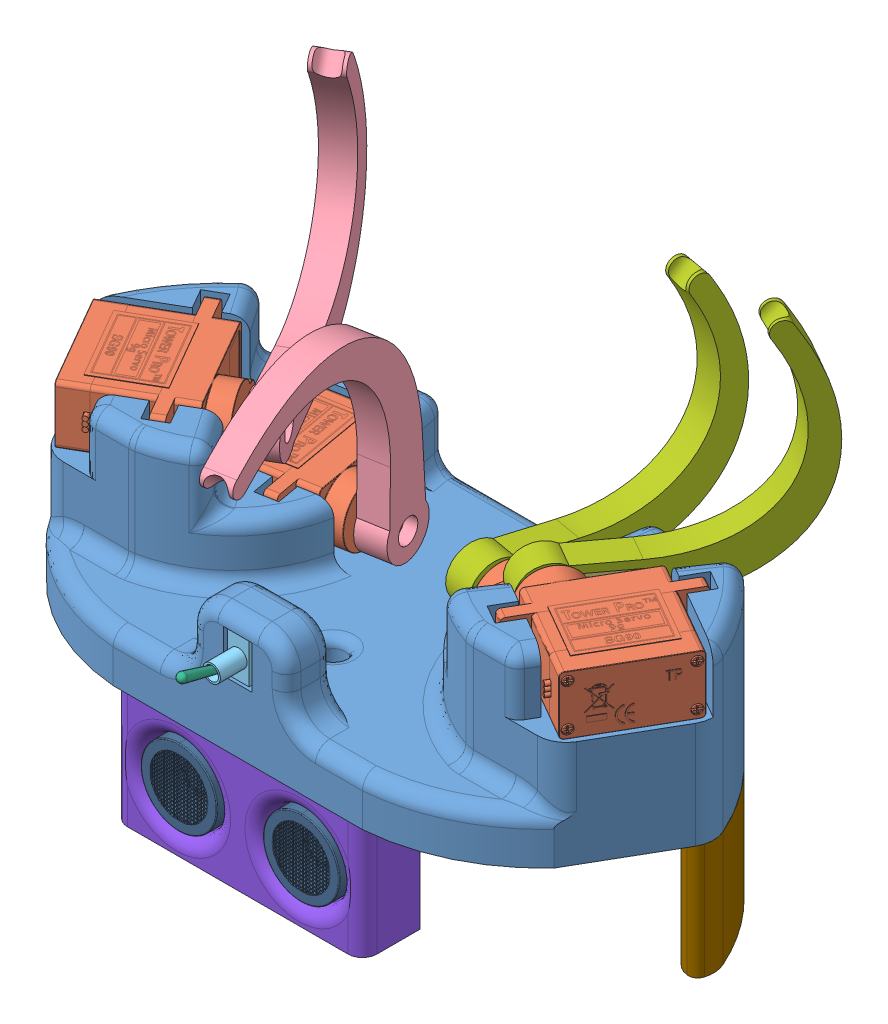
SolidWorks assembly ASSEMBLY, configuration Default. Lengths in mm.
Overall size (132.6 96.26 103.99).
20 component instances, 11 part files, 48 mates.
Components (placement in the parent):
- Body V1-1: Body V1 [Default] at (-17.087 -21.5475 12.8417) size (129.75 34.69 65.17)
- servo-1: servo [Peça] at (-48.2821 -15.4475 -6.8681) x (-0.173648 0 -0.984808) z (0 -1 0) size (32.1 29.95 12.4)
- Part1^ASSEMBLY-1: Part1^ASSEMBLY [Default] at origin (virtual)
- servo-2: servo [Peça] at (-66.1387 -3.2475 7.2816) x (-0.5 0 -0.866025) z (0 -1 0) size (32.1 29.95 12.4)
- servo-3: servo [Peça] at (31.9648 -3.2475 7.2816) x (0.5 0 -0.866025) z (0 1 0) size (32.1 29.95 12.4)
- servo-4: servo [Peça] at (14.1082 -15.4475 -6.8681) x (0.173648 0 -0.984808) z (0 1 0) size (32.1 29.95 12.4)
- servo horn-1: servo horn [Peça] at (-7.5656 -15.4475 -5.4603) x (-0.17349 0.042632 0.983912) z (-0.007403 -0.999091 0.041984) size (19.5 3.8 6.9)
- servo horn-2: servo horn [Peça] at (11.1166 -3.2475 1.1916) x (-0.499797 0.028461 0.865675) z (-0.014231 -0.999595 0.024648) size (19.5 3.8 6.9)
- servo horn-3: servo horn [Peça] at (-45.2906 -3.2475 1.1916) x (0.499982 0.008414 0.865995) z (-0.004207 0.999965 -0.007287) size (19.5 3.8 6.9)
- servo horn-4: servo horn [Peça] at (-26.6084 -15.4475 -5.4603) x (-0.006569 -0.999284 -0.037255) z (0.173524 -0.037829 0.984103) size (19.5 3.8 6.9)
- Servo Arm-1: Servo Arm [Default] at (-48.3216 -3.2475 2.9416) x (0.499982 0.008414 0.865995) z (0.866025 0 -0.5) size (52.95 49.27 6)
- Servo Arm-2: Servo Arm [Default] at (-30.0552 -15.4475 -4.8526) x (-0.006569 -0.999284 -0.037255) z (0.984808 0 -0.173648) size (52.95 49.27 6)
- Switch_p1-1: Switch_p1 [Défaut] at (-20.4383 -19.9265 28.9316) x (1 0 0) z (0 -1 0) size (4.44 13.93 8.26)
- Switch_p2-1: Switch_p2 [Défaut] at (-16.9811 -14.1901 37.8393) x (1 0 0) z (0 -0.961262 0.275637) size (3.2 9.83 1.92)
- Servo Arm flipped-1: Servo Arm flipped [Default] at (74.6659 -15.4475 9.0393) x (-0.17349 0.042632 0.983912) z (0.984808 0 0.173648) size (52.95 49.27 6)
- Servo Arm flipped-2: Servo Arm flipped [Default] at (83.4297 -3.2475 42.9416) x (-0.499797 0.028461 0.865675) z (0.866025 0 0.5) size (52.95 49.27 6)
- ultrasonic holder-1: ultrasonic holder [Default] at (-17.087 -43.5475 24.6865) x (1 0 0) z (0 -1 0) size (52 12 24)
- Leg-1: Leg [Default] at (-17.2696 -55.5475 -11.7392) x (-0.999978 0 0.006606) z (-0.006606 0 -0.999978) size (45.94 24 33.42)
- Leg-2: Leg [Default] at (-17.087 -31.5475 -11.596) x (1 0 0) z (0 0 -1) size (45.94 24 33.42)
- ultrasonic sonsor-1: ultrasonic sonsor [Default] at (-17.087 -43.5475 22.6339) x (1 0 0) z (0 -1 0) size (45.5 21.95 20.5)
Mates (geometry in assembly coordinates):
- Distance3: distance = 1 mm anti-aligned: plane of servo-1 through (-45.1639 -20.6975 -18.8415) normal (-0.173648 0 -0.984808); plane of Body V1-1 through (-61.7838 -9.3475 -16.9264) normal (0.173648 0 0.984808)
- Coincident6: coincident anti-aligned: plane of Body V1-1 through (-17.087 -21.5475 12.8417) normal (0 1 0); plane of servo-1 through (-38.1089 -21.5475 6.7726) normal (0 -1 0)
- Distance4: distance = 1 mm anti-aligned: plane of servo-1 through (-38.1089 -20.6975 6.7726) normal (0.984808 0 -0.173648); plane of Body V1-1 through (-42.7242 -9.3475 -25.1611) normal (-0.984808 0 0.173648)
- Coincident11: coincident anti-aligned: plane of Body V1-1 through (-17.087 -9.3475 12.8417) normal (0 1 0); plane of servo-2 through (-51.9136 -9.3475 16.6202) normal (0 -1 0)
- Distance7: distance = 1 mm anti-aligned: plane of servo-2 through (-54.0787 -8.4975 17.8702) normal (-0.866025 0 0.5); plane of Body V1-1 through (-47.8742 2.8525 30.6167) normal (0.866025 0 -0.5)
- Distance8: distance = 1 mm anti-aligned: plane of servo-2 through (-19.7634 -8.4975 -32.4836) normal (-0.5 0 -0.866025); plane of Body V1-1 through (-37.8825 2.8525 -23.1772) normal (0.5 0 0.866025)
- Coincident17: coincident anti-aligned: plane of Body V1-1 through (-17.087 -21.5475 12.8417) normal (0 1 0); plane of servo-4 through (22.6919 -21.5475 5.2059) normal (0 -1 0)
- Distance11: distance = 1 mm anti-aligned: plane of servo-4 through (7.0829 -10.1975 3.3167) normal (-0.173648 0 0.984808); plane of Body V1-1 through (7.894 -9.3475 4.4752) normal (0.173648 0 -0.984808)
- Distance12: distance = 1 mm anti-aligned: plane of servo-4 through (22.6919 -10.1975 5.2059) normal (0.984808 0 0.173648); plane of Body V1-1 through (23.3555 -9.3475 7.2014) normal (-0.984808 0 -0.173648)
- Coincident20: coincident anti-aligned: plane of Body V1-1 through (-17.087 -9.3475 12.8417) normal (0 1 0); plane of servo-3 through (17.7397 -9.3475 16.6202) normal (0 -1 0)
- Distance13: distance = 1 mm anti-aligned: plane of servo-3 through (33.1297 2.0025 -5.0362) normal (0.5 0 -0.866025); plane of Body V1-1 through (3.7086 2.8525 -23.1772) normal (-0.5 0 0.866025)
- Distance14: distance = 1 mm anti-aligned: plane of Body V1-1 through (9.8031 2.8525 28.3667) normal (0.866025 0 0.5); plane of servo-3 through (17.7397 2.0025 16.6202) normal (-0.866025 0 -0.5)
- Coincident23: coincident anti-aligned: plane of servo-1 through (-28.381 -15.4475 -5.1478) normal (0.984808 0 -0.173648); plane of servo horn-4 through (-28.381 -15.4475 -5.1478) normal (-0.984808 0 0.173648)
- Concentric1: concentric aligned: circle of servo-1; circle of servo horn-4
- Coincident24: coincident anti-aligned: plane of servo-4 through (-5.7929 -15.4475 -5.1478) normal (-0.984808 0 -0.173648); plane of servo horn-1 through (-5.7929 -15.4475 -5.1478) normal (0.984808 0 0.173648)
- Concentric2: concentric anti-aligned: circle of servo-4; circle of servo horn-1
- Coincident25: coincident anti-aligned: plane of servo-3 through (12.6755 -3.2475 2.0916) normal (-0.866025 0 -0.5); plane of servo horn-2 through (12.6755 -3.2475 2.0916) normal (0.866025 0 0.5)
- Concentric3: concentric anti-aligned: circle of servo-3; circle of servo horn-2
- Coincident26: coincident anti-aligned: plane of servo-2 through (-46.8494 -3.2475 2.0916) normal (0.866025 0 -0.5); plane of servo horn-3 through (-46.8494 -3.2475 2.0916) normal (-0.866025 0 0.5)
- Concentric4: concentric aligned: circle of servo-2; circle of servo horn-3
- Coincident27: coincident anti-aligned: plane of servo horn-3 through (-45.2906 -3.2475 1.1916) normal (0.866025 0 -0.5); plane of Servo Arm-1 through (-52.3153 -3.3658 -10.9756) normal (-0.866025 0 0.5)
- Concentric5: concentric anti-aligned: circle of servo horn-3; circle of Servo Arm-1
- Concentric6: concentric anti-aligned: cylinder of servo horn-3 through (-53.5277 -3.3658 -10.2756) axis (0.866025 0 -0.5) radius 2; cylinder of Servo Arm-1 through (-52.3153 -3.3658 -10.9756) axis (-0.866025 0 0.5) radius 2.4
- Coincident28: coincident anti-aligned: plane of servo horn-4 through (-26.6084 -15.4475 -5.4603) normal (0.984808 0 -0.173648); plane of Servo Arm-2 through (-26.5161 -1.4076 -4.9369) normal (-0.984808 0 0.173648)
- Concentric7: concentric anti-aligned: circle of servo horn-4; circle of Servo Arm-2
- Concentric8: concentric anti-aligned: cylinder of servo horn-4 through (-27.8948 -1.4076 -4.6938) axis (0.984808 0 -0.173648) radius 2; cylinder of Servo Arm-2 through (-26.5161 -1.4076 -4.9369) axis (-0.984808 0 0.173648) radius 2.4
- Coincident33: coincident anti-aligned: plane of Switch_p1-1 through (-15.3807 -13.4744 40.3353) normal (-1 0 0); plane of Switch_p2-1 through (-15.3807 -13.4744 40.3353) normal (1 0 0)
- Concentric10: concentric anti-aligned: circle of Switch_p1-1; circle of Switch_p2-1
- Coincident34: coincident anti-aligned: plane of Body V1-1 through (-20.027 -9.3475 21.4865) normal (0 -1 0); plane of Switch_p1-1 through (-19.1896 -9.3475 36.6865) normal (0 1 0)
- Distance15: distance = 0.6 mm anti-aligned: plane of Switch_p1-1 through (-14.747 -17.6055 36.6865) normal (1 0 0); plane of Body V1-1 through (-14.147 -9.3475 21.4865) normal (-1 0 0)
- Coincident36: coincident aligned: plane of Body V1-1 through (-17.087 -31.5475 36.6865) normal (0 0 1); plane of Switch_p1-1 through (-19.1896 -17.6055 36.6865) normal (0 0 1)
- Coincident37: coincident anti-aligned: plane of servo horn-2 through (11.1166 -3.2475 1.1916) normal (-0.866025 0 -0.5); plane of Servo Arm flipped-2 through (18.1388 -3.6474 -10.9711) normal (0.866025 0 0.5)
- Concentric11: concentric anti-aligned: cylinder of servo horn-2 through (12.3291 -3.2475 1.8916) axis (-0.866025 0 -0.5) radius 3.45; cylinder of Servo Arm flipped-2 through (11.1166 -3.2475 1.1916) axis (0.866025 0 0.5) radius 3.85
- Concentric12: concentric anti-aligned: cylinder of servo horn-2 through (19.3512 -3.6474 -10.2711) axis (-0.866025 0 -0.5) radius 2; cylinder of Servo Arm flipped-2 through (18.1388 -3.6474 -10.9711) axis (0.866025 0 0.5) radius 2.4
- Coincident38: coincident anti-aligned: plane of servo horn-1 through (-7.5656 -15.4475 -5.4603) normal (-0.984808 0 -0.173648); plane of Servo Arm flipped-1 through (-5.128 -16.0465 -19.2843) normal (0.984808 0 0.173648)
- Concentric13: concentric anti-aligned: cylinder of servo horn-1 through (-6.1868 -15.4475 -5.2172) axis (-0.984808 0 -0.173648) radius 3.45; cylinder of Servo Arm flipped-1 through (-11.0124 -15.4475 -6.0681) axis (0.984808 0 0.173648) radius 2.5
- Concentric14: concentric anti-aligned: cylinder of servo horn-1 through (-3.7493 -16.0465 -19.0412) axis (-0.984808 0 -0.173648) radius 2; cylinder of Servo Arm flipped-1 through (-5.128 -16.0465 -19.2843) axis (0.984808 0 0.173648) radius 2.4
- Coincident39: coincident anti-aligned: plane of Body V1-1 through (-17.087 -31.5475 12.8417) normal (0 -1 0); plane of ultrasonic holder-1 through (-43.087 -31.5475 36.6865) normal (0 1 0)
- Coincident40: coincident aligned: plane of Body V1-1 through (-17.087 -31.5475 36.6865) normal (0 0 1); plane of ultrasonic holder-1 through (-17.087 -43.5475 36.6865) normal (0 0 1)
- Coincident41: coincident: line of Body V1-1 through (8.913 -31.5475 36.6865) axis (0 1 0); plane of ultrasonic holder-1 through (8.913 -31.5475 36.6865) normal (1 0 0)
- Coincident43: coincident anti-aligned: plane of Body V1-1 through (-17.087 -31.5475 12.8417) normal (0 -1 0); plane of Leg-1 through (-56.9835 -31.5475 10.3631) normal (0 1 0)
- Coincident44: coincident: point of Body V1-1; point of Leg-1
- Coincident47: coincident: cylinder of Leg-1 through (-38.2654 -31.5475 18.506) axis (0 -1 0) radius 46.8252; line of Body V1-1 through (-81.0764 -31.5475 -0.4627) axis (0 1 0)
- Coincident48: coincident anti-aligned: plane of Body V1-1 through (-17.087 -31.5475 12.8417) normal (0 -1 0); plane of Leg-2 through (22.7721 -31.5475 10.2434) normal (0 1 0)
- Coincident49: coincident: point of Body V1-1; point of Leg-2
- Coincident51: coincident: line of Body V1-1 through (46.9219 -0.1475 -0.4528) axis (0 -1 0); point of Leg-2
- Concentric17: concentric aligned: cylinder of ultrasonic holder-1 through (-29.837 -43.5475 36.6865) axis (0 0 -1) radius 8.25; cylinder of ultrasonic sonsor-1 through (-29.837 -43.5475 36.2339) axis (0 0 -1) radius 7.95
- Concentric18: concentric aligned: cylinder of ultrasonic holder-1 through (-4.337 -43.5475 36.6865) axis (0 0 -1) radius 8.25; cylinder of ultrasonic sonsor-1 through (-4.337 -43.5475 36.2339) axis (0 0 -1) radius 7.95
